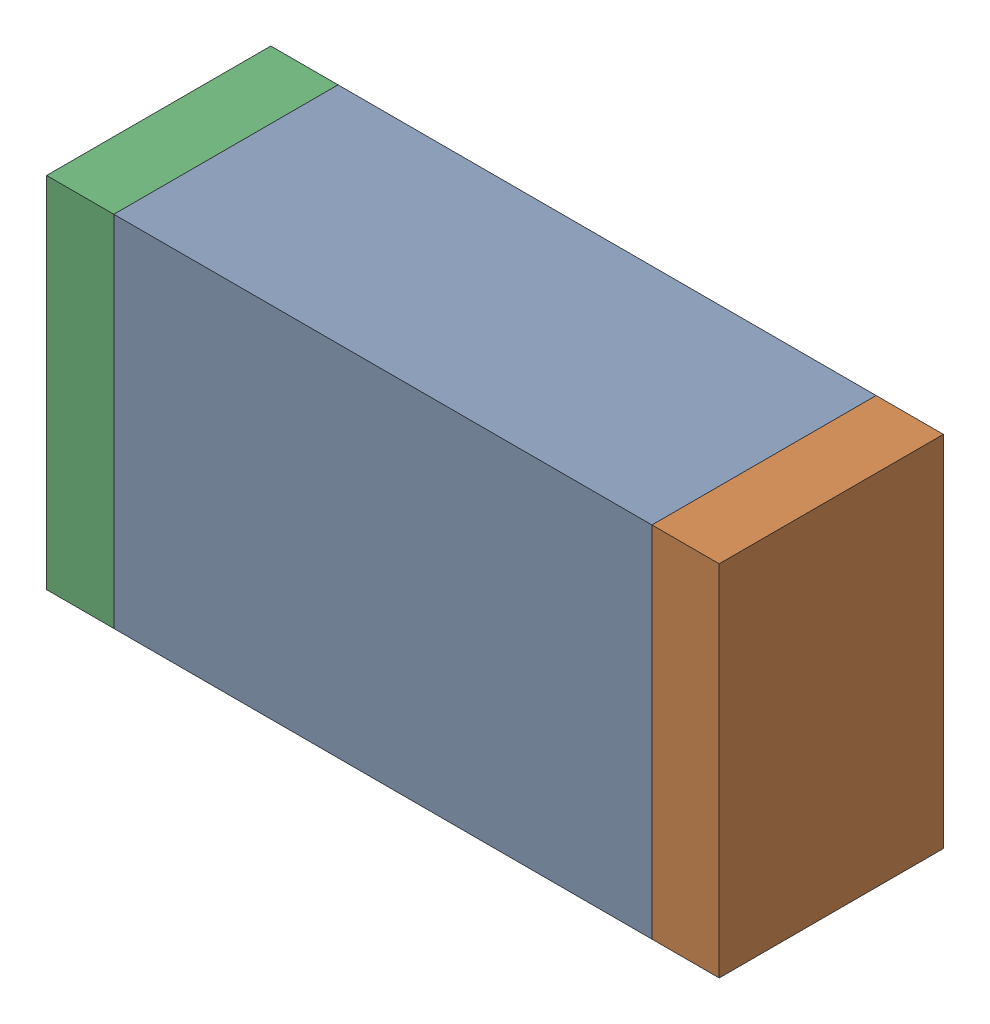
SolidWorks assembly C7, configuration Default. Lengths in mm.
Overall size (1.5 0.8 0.5).
6 component instances, 2 part files, 0 mates.
Components (placement in the parent):
- 836752368-1: 836752368 [Default] at (128.45 8.15 0) size (1.2 0.8 0.5)
  - Extruded-1: Extruded [Default] at origin size (1.2 0.8 0.5)
- 836752496-1: 836752496 [Default] at (129.125 8.15 0) size (0.15 0.8 0.5)
  - Extruded_2-1: Extruded_2 [Default] at origin size (0.15 0.8 0.5)
- 836752496-2: 836752496 [Default] at (127.775 8.15 0) size (0.15 0.8 0.5)
  - Extruded_2-1: Extruded_2 [Default] at origin size (0.15 0.8 0.5)
